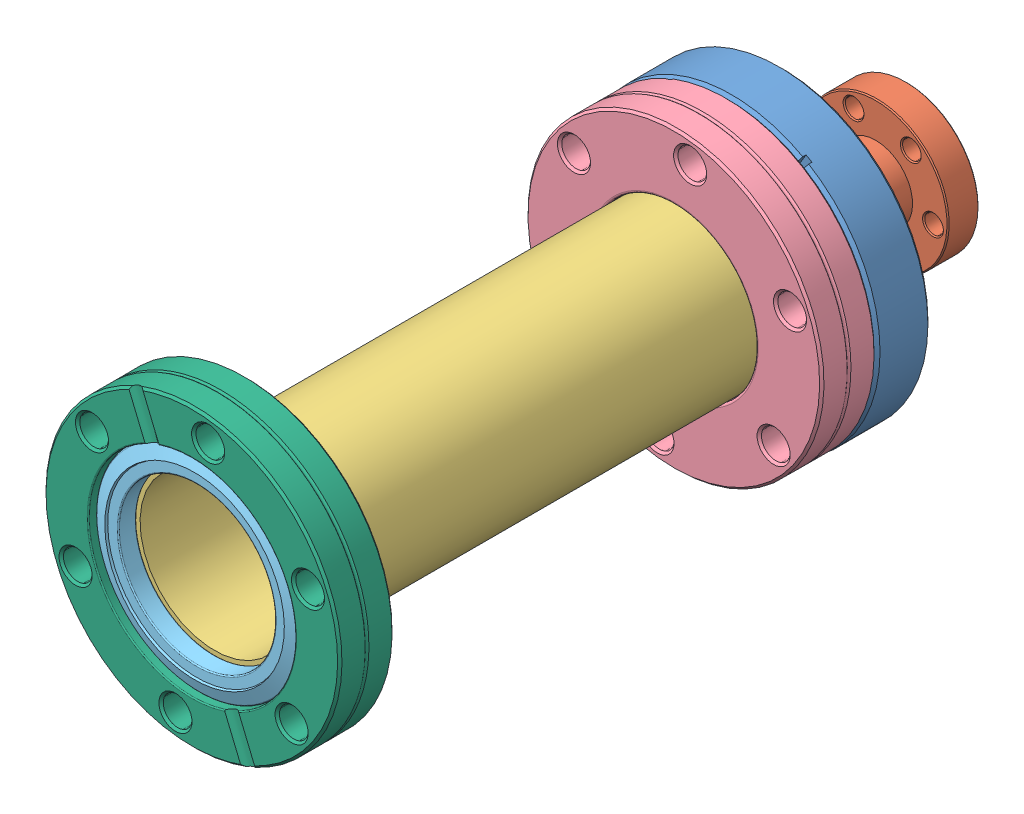
SolidWorks assembly Er Source, configuration Default. Lengths in mm.
Overall size (90.28 90.28 166.89).
10 component instances, 6 part files, 2 mates.
Components (placement in the parent):
- Er Source P1-1: Er Source P1 [Default] at (43.5745 11.2308 -16.1457) size (69.34 69.34 41.66)
  - Er Source P1-2_110008-1: Er Source P1-2_110008 [Default] at (13.1702 33.8948 67.8415) size (69.34 69.34 12.7)
  - Er Source P1-1_110002-1: Er Source P1-1_110002 [Default] at (13.1702 33.8948 26.1855) x (-0.923728 -0.383049 0) z (0 0 -1) size (33.78 33.78 28.96)
- Er Source P2_fn-0275-1: Er Source P2_fn-0275 [Default] at (56.7446 45.1256 58.0458) x (-0.923728 -0.383049 0) z (0 0 -1) size (69.09 69.09 125.37)
  - Er Source P2-2_A0001676-1: Er Source P2-2_A0001676 [Default] at origin size (69.09 69.09 120.02)
    - Er Source P2-2-2_P0001614-1: Er Source P2-2-2_P0001614 [Default] at (0 0 -56.2483) x (0 1 0) z (0 0 -1) size (38.1 38.1 114.58)
    - Er Source P2-2-1_P0000127-1: Er Source P2-2-1_P0000127 [Default] at origin size (69.09 69.09 12.84)
  - A0000603-1: A0000603 [Default] at (0 0 -106.1466) x (1 0 0) z (0 0 -1) size (69.09 69.09 12.74)
    - Er Source P2-1-2_P0000489-1: Er Source P2-1-2_P0000489 [Default] at (0 0 8.5725) size (48.21 48.21 6.99)
    - Er Source P2-1-1_P0000436-1: Er Source P2-1-1_P0000436 [Default] at (0 0 6.35) x (-1 0 0) z (0 0 -1) size (69.09 69.09 12.74)
Mates (geometry in assembly coordinates):
- Coincident1: coincident anti-aligned: plane of Er Source P1-1/Er Source P1-2_110008-1 through (56.7446 45.1256 51.6958) normal (0 0 1); plane of Er Source P2_fn-0275-1/Er Source P2-2_A0001676-1/Er Source P2-2-1_P0000127-1 through (56.7446 45.1256 51.6958) normal (0 0 -1)
- Concentric1: concentric anti-aligned: circle of Er Source P1-1/Er Source P1-2_110008-1; circle of Er Source P2_fn-0275-1/Er Source P2-2_A0001676-1/Er Source P2-2-1_P0000127-1
